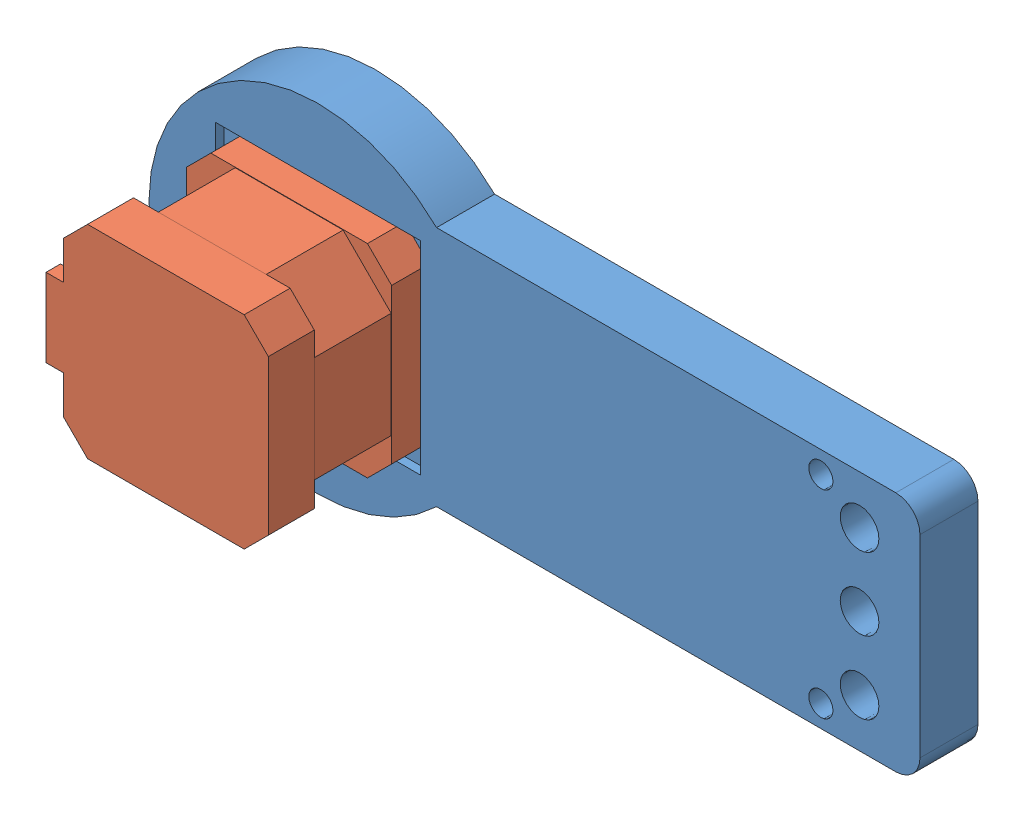
SolidWorks assembly Ensamblaje_Link2, configuration Predeterminado. Lengths in mm.
Overall size (159.49 70 55.2).
2 component instances, 2 part files, 6 mates.
Components (placement in the parent):
- Pieza2-1: Pieza2 [Predeterminado] x (0 1 0) z (1 0 0) size (70 12 159.49)
- Motor Paso a Paso-1: Motor Paso a Paso [Predeterminado] at (-111.9949 0 43.5) x (0 1 0) z (-1 0 0) size (42 55.2 46)
Mates (geometry in assembly coordinates):
- Coincidente1: coincident aligned: plane of Pieza2-1 through (0 0 0) normal (0 0 1)
- Coincidente2: coincident aligned: plane of Pieza2-1 through (0 0 0) normal (1 0 0)
- Coincidente4: coincident aligned: plane of Pieza2-1 through (0 0 0) normal (0 1 0)
- Concéntrica1: concentric: cylinder of Pieza2-1 through (-111.9949 0 8.3) axis (0 0 1) radius 11; cylinder of Motor Paso a Paso-1 through (-111.9949 0 8.3) axis (0 0 1) radius 11
- Coincidente5: coincident: plane of Pieza2-1 through (-133.1949 -21 10.3) normal (1 0 0); plane of Motor Paso a Paso-1 through (-133.1949 -16 10.3) normal (-1 0 0)
- Coincidente6: coincident anti-aligned: plane of Pieza2-1 through (0 0 10.3) normal (0 0 1); plane of Motor Paso a Paso-1 through (-111.9949 0 10.3) normal (0 0 -1)
